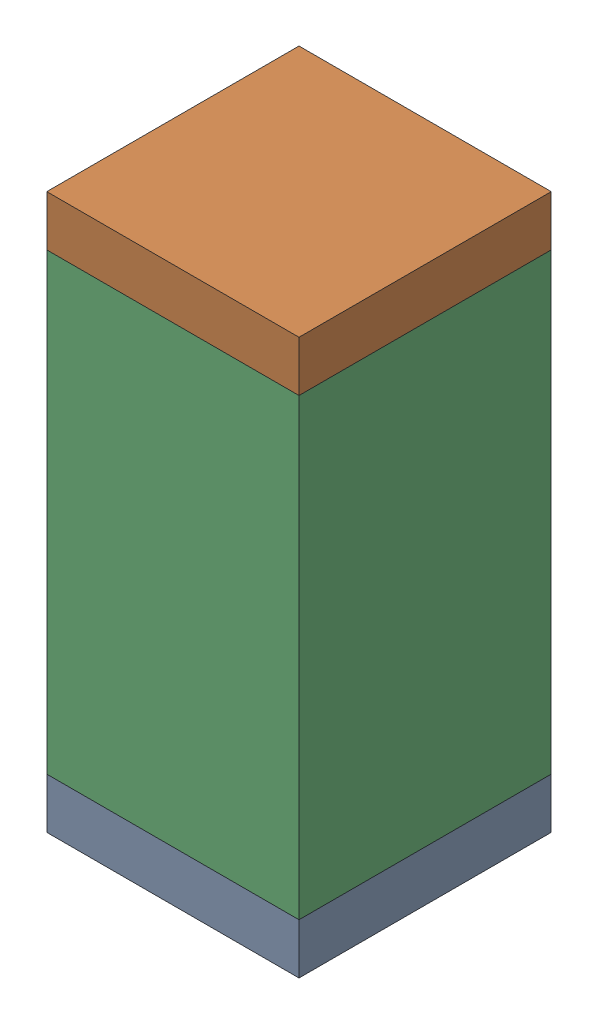
SolidWorks assembly C111, configuration Default. Lengths in mm.
Overall size (0.5 1.1 0.5).
6 component instances, 2 part files, 0 mates.
Components (placement in the parent):
- 810157360-1: 810157360 [Default] at (116.75 79 0) size (0.5 0.1 0.5)
  - Extruded_9-1: Extruded_9 [Default] at origin size (0.5 0.1 0.5)
- 810157360-2: 810157360 [Default] at (116.75 80 0) size (0.5 0.1 0.5)
  - Extruded_9-1: Extruded_9 [Default] at origin size (0.5 0.1 0.5)
- 791586336-1: 791586336 [Default] at (116.75 79.5 0) size (0.5 0.9 0.5)
  - Extruded_8-1: Extruded_8 [Default] at origin size (0.5 0.9 0.5)
